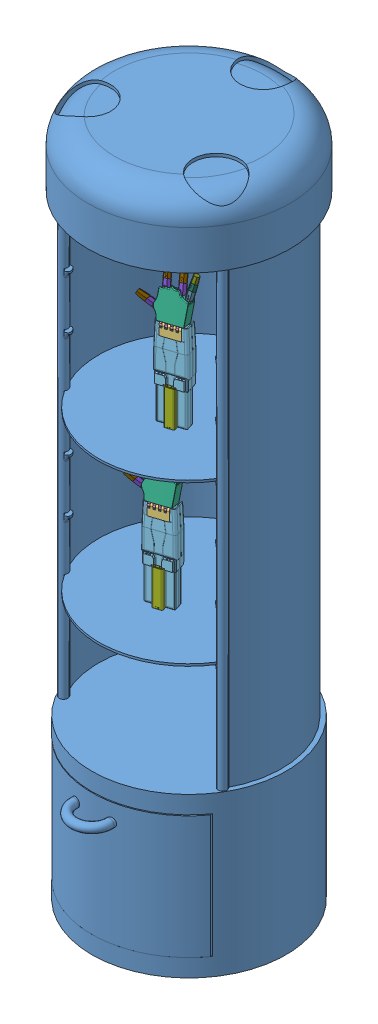
SolidWorks assembly trophy assembly, configuration Default. Lengths in mm.
Overall size (581.67 1961.55 633.74).
107 component instances, 18 part files, 2 mates.
Components (placement in the parent):
- trophy-case-1: trophy-case [Default] at (-1.6305 -991.4649 -17.9092) size (581.67 1961.55 633.74)
- Assembly 12.13-1: Assembly 12.13 [Jets] at (-34.9055 379.5581 -19.7967) x (0.972274 -0.189198 -0.137429) z (-0.137429 -0.937807 0.318797) size (189.41 135.67 392.55)
  - blaster 12.13-1: blaster 12.13 [Default] at (10.8365 93.5014 -120.4918) x (-0.62543 0.020048 0.780022) z (0.769171 -0.152244 0.620643) size (38.1 6.35 38.1)
  - Hinge 1-4: Hinge 1 [Default] at (28.2843 111.7206 -64.6458) x (0.967149 -0.109898 -0.229227) z (-0.192555 0.272009 -0.942833) size (50.8 12.7 33.67)
  - Hinge 2-4: Hinge 2 [Default] at (21.3186 112.3612 -94.3427) x (-0.967149 0.109898 0.229227) z (0.131196 0.98814 0.079798) size (50.8 34.01 12.7)
  - Forearm-klwz-1: Forearm-klwz [Jets] at (20.8409 98.0499 -89.4966) x (-0.967149 0.109898 0.229227) z (-0.189198 0.291071 -0.937807) size (82.55 44.71 254)
  - Glove-KLWZ-1: Glove-KLWZ [Jets] at (-11.4933 90.7479 -81.5127) x (0.967149 -0.109898 -0.229227) z (0.217739 -0.10725 0.970097) size (80.65 34.73 87.6)
  - Rocket-KLWZ-4: Rocket-KLWZ [Jets] at (83.0956 33.4453 148.7368) x (-0.967149 0.109898 0.229227) z (-0.169784 -0.950368 -0.260717) size (25.4 101.6 15.24)
  - Index,Ring Finger-KLWZ-1: Index,Ring Finger-KLWZ [Default] at (-47.2445 89.7147 -150.9868) x (-0.210862 0.156828 -0.964853) z (0.967149 -0.109898 -0.229227) size (75.8 17.12 17.91)
    - Index,Ring Bottom-KLWZ-1: Index,Ring Bottom-KLWZ [Default] at (-10.8929 30.6765 25.4038) size (30.48 17.11 17.82)
    - Index,Ring Middle-KLWZ-1: Index,Ring Middle-KLWZ [Default] at (16.7849 30.6765 25.4038) size (26.67 16.95 17.91)
    - Index,Ring Tip-KLWZ-1: Index,Ring Tip-KLWZ [Default] at (39.5019 30.2308 25.4038) size (26.68 17.04 17.2)
    - Hinge Pin-KLWZ-1: Hinge Pin-KLWZ [Default] at (16.7849 22.9775 32.7698) x (1 0 0) z (0 -1 0) size (1.27 1.52 1.27)
    - Hinge Pin-KLWZ-2: Hinge Pin-KLWZ [Default] at (16.7849 22.9775 16.5138) x (1 0 0) z (0 -1 0) size (1.27 1.52 1.27)
    - Hinge Pin-KLWZ-3: Hinge Pin-KLWZ [Default] at (39.5019 22.8618 16.8939) x (1 0 0) z (0 -1 0) size (1.27 1.52 1.27)
    - Hinge Pin-KLWZ-4: Hinge Pin-KLWZ [Default] at (39.5019 22.8618 32.3896) x (1 0 0) z (0 -1 0) size (1.27 1.52 1.27)
    - Hinge 3-KLWZ-1: Hinge 3-KLWZ [Default] at (-6.7857 12.0092 22.8683) x (0.998734 -0.050311 0) z (0 0 1) size (2.55 0.58 2.54) (flexible)
      - Hinge 3-KLWZ-1: Hinge 3-KLWZ [Default] at (1.5197 1.8887 1.2654) size (1.52 0.51 2.54)
      - Hinge 3-KLWZ-2: Hinge 3-KLWZ [Default] at (1.5197 1.8887 3.8054) x (-0.998734 -0.050311 0) z (0 0 -1) size (1.52 0.51 2.54)
      - Hinge 3 Pin-KLWZ-1: Hinge 3 Pin-KLWZ [Default] at (1.5197 1.8887 3.8054) x (1 0 0) z (0 1 0) size (0.25 2.54 0.25)
  - Pinky Finger-KLWZ-1: Pinky Finger-KLWZ [Default] at (9.46 93.3984 -161.1362) x (0.009195 0.129763 -0.991502) z (0.991353 -0.130981 -0.007948) size (60.63 17.12 17.87)
    - Pinky Bottom-KLWZ-1: Pinky Bottom-KLWZ [Default] at (-10.9157 20.3951 24.52) size (25.4 17.11 17.82)
    - Pinky Middle-KLWZ-1: Pinky Middle-KLWZ [Default] at (11.6821 20.3951 24.52) size (21.59 16.79 17.87)
    - Pinky Tip-KLWZ-1: Pinky Tip-KLWZ [Default] at (29.3929 19.6656 24.52) size (21.6 16.32 16.67)
    - Hinge Pin-KLWZ-1: Hinge Pin-KLWZ [Default] at (11.6821 12.6961 31.886) x (1 0 0) z (0 -1 0) size (1.27 1.52 1.27)
    - Hinge Pin-KLWZ-2: Hinge Pin-KLWZ [Default] at (29.3929 12.5166 31.2975) x (1 0 0) z (0 -1 0) size (1.27 1.52 1.27)
    - Hinge Pin-KLWZ-3: Hinge Pin-KLWZ [Default] at (11.6821 12.6961 15.63) x (1 0 0) z (0 -1 0) size (1.27 1.52 1.27)
    - Hinge Pin-KLWZ-4: Hinge Pin-KLWZ [Default] at (29.3929 12.5166 16.2186) x (1 0 0) z (0 -1 0) size (1.27 1.52 1.27)
    - Hinge 3-KLWZ-1: Hinge 3-KLWZ [Default] at (-6.8084 1.7278 21.9846) x (0.998734 -0.050311 0) z (0 0 1) size (2.55 0.58 2.54) (flexible)
      - Hinge 3-KLWZ-1: Hinge 3-KLWZ [Default] at (1.5197 1.8887 1.2654) size (1.52 0.51 2.54)
      - Hinge 3-KLWZ-2: Hinge 3-KLWZ [Default] at (1.5197 1.8887 3.8054) x (-0.998734 -0.050311 0) z (0 0 -1) size (1.52 0.51 2.54)
      - Hinge 3 Pin-KLWZ-1: Hinge 3 Pin-KLWZ [Default] at (1.5197 1.8887 3.8054) x (1 0 0) z (0 1 0) size (0.25 2.54 0.25)
  - Thumb Finger-KLWZ-1: Thumb Finger-KLWZ [Default] at (-39.7971 88.5121 -75.6592) x (-0.961322 0.194314 -0.1952) z (0.208655 0.051167 -0.97665) size (55.96 18.36 17.96)
    - Thumb Bottom-KLWZ-1: Thumb Bottom-KLWZ [Default] at (-12.3688 24.9437 27.5572) size (30.48 17.11 17.82)
    - Thumb Tip-KLWZ-1: Thumb Tip-KLWZ [Default] at (15.309 24.9437 27.5572) size (29.55 18.36 17.96)
    - Hinge Pin-KLWZ-1: Hinge Pin-KLWZ [Default] at (15.309 17.2447 18.6672) x (1 0 0) z (0 -1 0) size (1.27 1.52 1.27)
    - Hinge Pin-KLWZ-2: Hinge Pin-KLWZ [Default] at (15.309 17.2447 34.9232) x (1 0 0) z (0 -1 0) size (1.27 1.52 1.27)
    - Hinge 3-KLWZ-1: Hinge 3-KLWZ [Default] at (-8.2616 6.2764 25.0218) x (0.998734 -0.050311 0) z (0 0 1) size (2.55 0.58 2.54) (flexible)
      - Hinge 3-KLWZ-1: Hinge 3-KLWZ [Default] at (1.5197 1.8887 1.2654) size (1.52 0.51 2.54)
      - Hinge 3-KLWZ-2: Hinge 3-KLWZ [Default] at (1.5197 1.8887 3.8054) x (-0.998734 -0.050311 0) z (0 0 -1) size (1.52 0.51 2.54)
      - Hinge 3 Pin-KLWZ-1: Hinge 3 Pin-KLWZ [Default] at (1.5197 1.8887 3.8054) x (1 0 0) z (0 1 0) size (0.25 2.54 0.25)
  - Index,Ring Finger-KLWZ-2: Index,Ring Finger-KLWZ [Default] at (-11.8701 85.6951 -159.371) x (-0.210862 0.156828 -0.964853) z (0.967149 -0.109898 -0.229227) size (75.8 17.12 17.91)
    - Index,Ring Bottom-KLWZ-1: Index,Ring Bottom-KLWZ [Default] at (-10.8929 30.6765 25.4038) size (30.48 17.11 17.82)
    - Index,Ring Middle-KLWZ-1: Index,Ring Middle-KLWZ [Default] at (16.7849 30.6765 25.4038) size (26.67 16.95 17.91)
    - Index,Ring Tip-KLWZ-1: Index,Ring Tip-KLWZ [Default] at (39.5019 30.2308 25.4038) size (26.68 17.04 17.2)
    - Hinge Pin-KLWZ-1: Hinge Pin-KLWZ [Default] at (16.7849 22.9775 32.7698) x (1 0 0) z (0 -1 0) size (1.27 1.52 1.27)
    - Hinge Pin-KLWZ-2: Hinge Pin-KLWZ [Default] at (16.7849 22.9775 16.5138) x (1 0 0) z (0 -1 0) size (1.27 1.52 1.27)
    - Hinge Pin-KLWZ-3: Hinge Pin-KLWZ [Default] at (39.5019 22.8618 16.8939) x (1 0 0) z (0 -1 0) size (1.27 1.52 1.27)
    - Hinge Pin-KLWZ-4: Hinge Pin-KLWZ [Default] at (39.5019 22.8618 32.3896) x (1 0 0) z (0 -1 0) size (1.27 1.52 1.27)
    - Hinge 3-KLWZ-1: Hinge 3-KLWZ [Default] at (-6.7857 12.0092 22.8683) x (0.998734 -0.050311 0) z (0 0 1) size (2.55 0.58 2.54) (flexible)
      - Hinge 3-KLWZ-1: Hinge 3-KLWZ [Default] at (1.5197 1.8887 1.2654) size (1.52 0.51 2.54)
      - Hinge 3-KLWZ-2: Hinge 3-KLWZ [Default] at (1.5197 1.8887 3.8054) x (-0.998734 -0.050311 0) z (0 0 -1) size (1.52 0.51 2.54)
      - Hinge 3 Pin-KLWZ-1: Hinge 3 Pin-KLWZ [Default] at (1.5197 1.8887 3.8054) x (1 0 0) z (0 1 0) size (0.25 2.54 0.25)
  - Middle Finger-KLWZ-2: Middle Finger-KLWZ [Default] at (-34.3797 91.3698 -153.9324) x (-0.210862 0.156828 -0.964853) z (0.967149 -0.109898 -0.229227) (suppressed, hidden)
- Assembly 12.13-2: Assembly 12.13 [Jets] at (-60.1771 -77.6419 -10.9406) x (0.972274 -0.189198 -0.137429) z (-0.137429 -0.937807 0.318797) size (189.41 135.67 392.55)
  - blaster 12.13-1: blaster 12.13 [Default] at (10.8365 93.5014 -120.4918) x (-0.62543 0.020048 0.780022) z (0.769171 -0.152244 0.620643) size (38.1 6.35 38.1)
  - Hinge 1-4: Hinge 1 [Default] at (28.2843 111.7206 -64.6458) x (0.967149 -0.109898 -0.229227) z (-0.192555 0.272009 -0.942833) size (50.8 12.7 33.67)
  - Hinge 2-4: Hinge 2 [Default] at (21.3186 112.3612 -94.3427) x (-0.967149 0.109898 0.229227) z (0.131196 0.98814 0.079798) size (50.8 34.01 12.7)
  - Forearm-klwz-1: Forearm-klwz [Jets] at (20.8409 98.0499 -89.4966) x (-0.967149 0.109898 0.229227) z (-0.189198 0.291071 -0.937807) size (82.55 44.71 254)
  - Glove-KLWZ-1: Glove-KLWZ [Jets] at (-11.4933 90.7479 -81.5127) x (0.967149 -0.109898 -0.229227) z (0.217739 -0.10725 0.970097) size (80.65 34.73 87.6)
  - Rocket-KLWZ-4: Rocket-KLWZ [Jets] at (83.0956 33.4453 148.7368) x (-0.967149 0.109898 0.229227) z (-0.169784 -0.950368 -0.260717) size (25.4 101.6 15.24)
  - Index,Ring Finger-KLWZ-1: Index,Ring Finger-KLWZ [Default] at (-47.2445 89.7147 -150.9868) x (-0.210862 0.156828 -0.964853) z (0.967149 -0.109898 -0.229227) size (75.8 17.12 17.91)
    - Index,Ring Bottom-KLWZ-1: Index,Ring Bottom-KLWZ [Default] at (-10.8929 30.6765 25.4038) size (30.48 17.11 17.82)
    - Index,Ring Middle-KLWZ-1: Index,Ring Middle-KLWZ [Default] at (16.7849 30.6765 25.4038) size (26.67 16.95 17.91)
    - Index,Ring Tip-KLWZ-1: Index,Ring Tip-KLWZ [Default] at (39.5019 30.2308 25.4038) size (26.68 17.04 17.2)
    - Hinge Pin-KLWZ-1: Hinge Pin-KLWZ [Default] at (16.7849 22.9775 32.7698) x (1 0 0) z (0 -1 0) size (1.27 1.52 1.27)
    - Hinge Pin-KLWZ-2: Hinge Pin-KLWZ [Default] at (16.7849 22.9775 16.5138) x (1 0 0) z (0 -1 0) size (1.27 1.52 1.27)
    - Hinge Pin-KLWZ-3: Hinge Pin-KLWZ [Default] at (39.5019 22.8618 16.8939) x (1 0 0) z (0 -1 0) size (1.27 1.52 1.27)
    - Hinge Pin-KLWZ-4: Hinge Pin-KLWZ [Default] at (39.5019 22.8618 32.3896) x (1 0 0) z (0 -1 0) size (1.27 1.52 1.27)
    - Hinge 3-KLWZ-1: Hinge 3-KLWZ [Default] at (-6.7857 12.0092 22.8683) x (0.998734 -0.050311 0) z (0 0 1) size (2.55 0.58 2.54) (flexible)
      - Hinge 3-KLWZ-1: Hinge 3-KLWZ [Default] at (1.5197 1.8887 1.2654) size (1.52 0.51 2.54)
      - Hinge 3-KLWZ-2: Hinge 3-KLWZ [Default] at (1.5197 1.8887 3.8054) x (-0.998734 -0.050311 0) z (0 0 -1) size (1.52 0.51 2.54)
      - Hinge 3 Pin-KLWZ-1: Hinge 3 Pin-KLWZ [Default] at (1.5197 1.8887 3.8054) x (1 0 0) z (0 1 0) size (0.25 2.54 0.25)
  - Pinky Finger-KLWZ-1: Pinky Finger-KLWZ [Default] at (9.46 93.3984 -161.1362) x (0.009195 0.129763 -0.991502) z (0.991353 -0.130981 -0.007948) size (60.63 17.12 17.87)
    - Pinky Bottom-KLWZ-1: Pinky Bottom-KLWZ [Default] at (-10.9157 20.3951 24.52) size (25.4 17.11 17.82)
    - Pinky Middle-KLWZ-1: Pinky Middle-KLWZ [Default] at (11.6821 20.3951 24.52) size (21.59 16.79 17.87)
    - Pinky Tip-KLWZ-1: Pinky Tip-KLWZ [Default] at (29.3929 19.6656 24.52) size (21.6 16.32 16.67)
    - Hinge Pin-KLWZ-1: Hinge Pin-KLWZ [Default] at (11.6821 12.6961 31.886) x (1 0 0) z (0 -1 0) size (1.27 1.52 1.27)
    - Hinge Pin-KLWZ-2: Hinge Pin-KLWZ [Default] at (29.3929 12.5166 31.2975) x (1 0 0) z (0 -1 0) size (1.27 1.52 1.27)
    - Hinge Pin-KLWZ-3: Hinge Pin-KLWZ [Default] at (11.6821 12.6961 15.63) x (1 0 0) z (0 -1 0) size (1.27 1.52 1.27)
    - Hinge Pin-KLWZ-4: Hinge Pin-KLWZ [Default] at (29.3929 12.5166 16.2186) x (1 0 0) z (0 -1 0) size (1.27 1.52 1.27)
    - Hinge 3-KLWZ-1: Hinge 3-KLWZ [Default] at (-6.8084 1.7278 21.9846) x (0.998734 -0.050311 0) z (0 0 1) size (2.55 0.58 2.54) (flexible)
      - Hinge 3-KLWZ-1: Hinge 3-KLWZ [Default] at (1.5197 1.8887 1.2654) size (1.52 0.51 2.54)
      - Hinge 3-KLWZ-2: Hinge 3-KLWZ [Default] at (1.5197 1.8887 3.8054) x (-0.998734 -0.050311 0) z (0 0 -1) size (1.52 0.51 2.54)
      - Hinge 3 Pin-KLWZ-1: Hinge 3 Pin-KLWZ [Default] at (1.5197 1.8887 3.8054) x (1 0 0) z (0 1 0) size (0.25 2.54 0.25)
  - Thumb Finger-KLWZ-1: Thumb Finger-KLWZ [Default] at (-39.7971 88.5121 -75.6592) x (-0.961322 0.194314 -0.1952) z (0.208655 0.051167 -0.97665) size (55.96 18.36 17.96)
    - Thumb Bottom-KLWZ-1: Thumb Bottom-KLWZ [Default] at (-12.3688 24.9437 27.5572) size (30.48 17.11 17.82)
    - Thumb Tip-KLWZ-1: Thumb Tip-KLWZ [Default] at (15.309 24.9437 27.5572) size (29.55 18.36 17.96)
    - Hinge Pin-KLWZ-1: Hinge Pin-KLWZ [Default] at (15.309 17.2447 18.6672) x (1 0 0) z (0 -1 0) size (1.27 1.52 1.27)
    - Hinge Pin-KLWZ-2: Hinge Pin-KLWZ [Default] at (15.309 17.2447 34.9232) x (1 0 0) z (0 -1 0) size (1.27 1.52 1.27)
    - Hinge 3-KLWZ-1: Hinge 3-KLWZ [Default] at (-8.2616 6.2764 25.0218) x (0.998734 -0.050311 0) z (0 0 1) size (2.55 0.58 2.54) (flexible)
      - Hinge 3-KLWZ-1: Hinge 3-KLWZ [Default] at (1.5197 1.8887 1.2654) size (1.52 0.51 2.54)
      - Hinge 3-KLWZ-2: Hinge 3-KLWZ [Default] at (1.5197 1.8887 3.8054) x (-0.998734 -0.050311 0) z (0 0 -1) size (1.52 0.51 2.54)
      - Hinge 3 Pin-KLWZ-1: Hinge 3 Pin-KLWZ [Default] at (1.5197 1.8887 3.8054) x (1 0 0) z (0 1 0) size (0.25 2.54 0.25)
  - Index,Ring Finger-KLWZ-2: Index,Ring Finger-KLWZ [Default] at (-11.8701 85.6951 -159.371) x (-0.210862 0.156828 -0.964853) z (0.967149 -0.109898 -0.229227) size (75.8 17.12 17.91)
    - Index,Ring Bottom-KLWZ-1: Index,Ring Bottom-KLWZ [Default] at (-10.8929 30.6765 25.4038) size (30.48 17.11 17.82)
    - Index,Ring Middle-KLWZ-1: Index,Ring Middle-KLWZ [Default] at (16.7849 30.6765 25.4038) size (26.67 16.95 17.91)
    - Index,Ring Tip-KLWZ-1: Index,Ring Tip-KLWZ [Default] at (39.5019 30.2308 25.4038) size (26.68 17.04 17.2)
    - Hinge Pin-KLWZ-1: Hinge Pin-KLWZ [Default] at (16.7849 22.9775 32.7698) x (1 0 0) z (0 -1 0) size (1.27 1.52 1.27)
    - Hinge Pin-KLWZ-2: Hinge Pin-KLWZ [Default] at (16.7849 22.9775 16.5138) x (1 0 0) z (0 -1 0) size (1.27 1.52 1.27)
    - Hinge Pin-KLWZ-3: Hinge Pin-KLWZ [Default] at (39.5019 22.8618 16.8939) x (1 0 0) z (0 -1 0) size (1.27 1.52 1.27)
    - Hinge Pin-KLWZ-4: Hinge Pin-KLWZ [Default] at (39.5019 22.8618 32.3896) x (1 0 0) z (0 -1 0) size (1.27 1.52 1.27)
    - Hinge 3-KLWZ-1: Hinge 3-KLWZ [Default] at (-6.7857 12.0092 22.8683) x (0.998734 -0.050311 0) z (0 0 1) size (2.55 0.58 2.54) (flexible)
      - Hinge 3-KLWZ-1: Hinge 3-KLWZ [Default] at (1.5197 1.8887 1.2654) size (1.52 0.51 2.54)
      - Hinge 3-KLWZ-2: Hinge 3-KLWZ [Default] at (1.5197 1.8887 3.8054) x (-0.998734 -0.050311 0) z (0 0 -1) size (1.52 0.51 2.54)
      - Hinge 3 Pin-KLWZ-1: Hinge 3 Pin-KLWZ [Default] at (1.5197 1.8887 3.8054) x (1 0 0) z (0 1 0) size (0.25 2.54 0.25)
  - Middle Finger-KLWZ-2: Middle Finger-KLWZ [Default] at (-34.3797 91.3698 -153.9324) x (-0.210862 0.156828 -0.964853) z (0.967149 -0.109898 -0.229227) (suppressed, hidden)
Mates (geometry in assembly coordinates):
- Coincident1: coincident anti-aligned: plane of trophy-case-1 through (-1.6305 234.0851 -17.9092) normal (0 1 0); plane of Assembly 12.13-1/Rocket-KLWZ-4 through (11.5179 234.0851 56.8185) normal (0 -1 0)
- Coincident2: coincident anti-aligned: plane of trophy-case-1 through (-1.6305 -223.1149 -17.9092) normal (0 1 0); plane of Assembly 12.13-2/Rocket-KLWZ-4 through (5.0986 -223.1149 60.3228) normal (0 -1 0)
